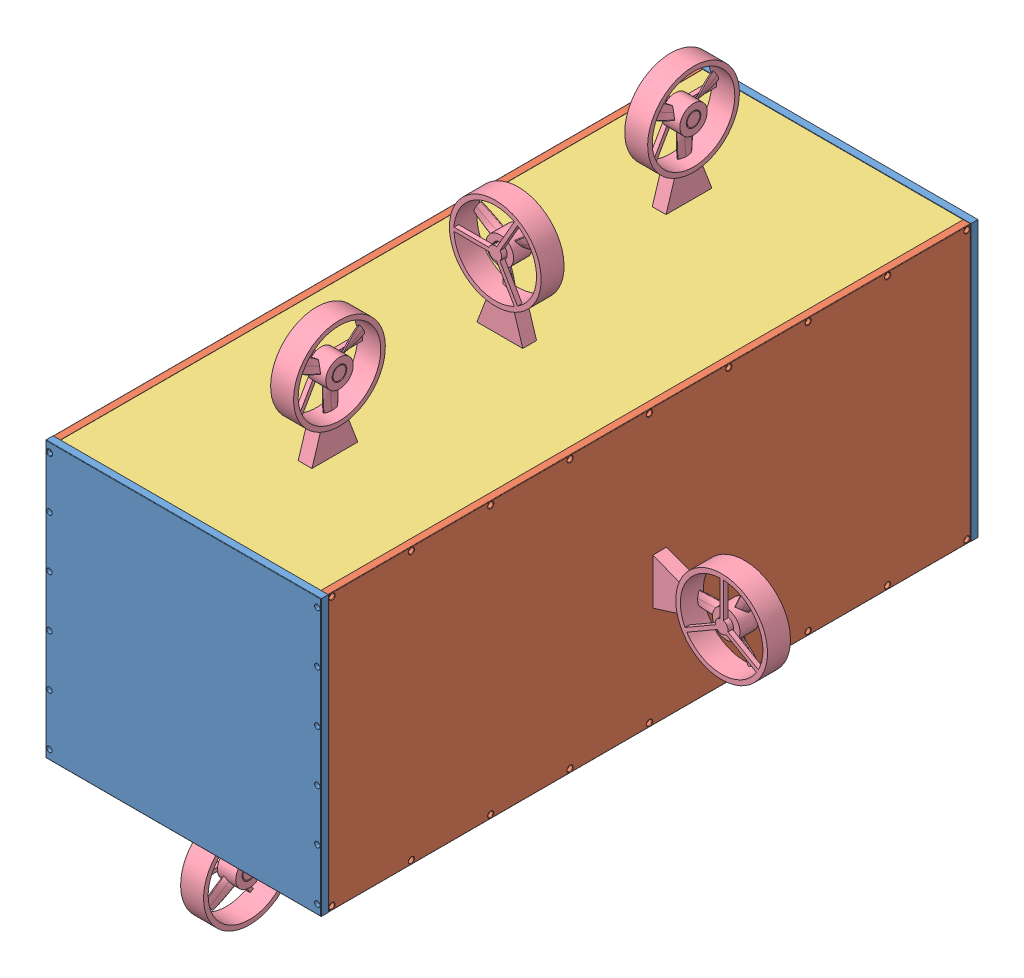
SolidWorks assembly square_assem, configuration Default. Lengths in mm.
Overall size (560 560 716).
14 component instances, 4 part files, 27 mates.
Components (placement in the parent):
- back_plate-1: back_plate [Default] at (111.4214 233.5106 160.385) size (300 300 8)
- side_plate-3: side_plate [Default] at (119.4214 233.5106 -539.615) x (0 0 1) z (-1 0 0) size (700 300 8)
- side_plate-4: side_plate [Default] at (403.4214 233.5106 160.385) x (0 0 -1) z (1 0 0) size (700 300 8)
- top_plate-3: top_plate [Default] at (119.4214 241.2606 160.385) x (0 0 -1) z (0 -1 0) size (700 284 8)
- top_plate-4: top_plate [Default] at (119.4214 533.2606 160.385) x (0 0 -1) z (0 -1 0) size (700 284 8)
- back_plate-2: back_plate [Default] at (111.4214 233.5106 -547.615) size (300 300 8)
- thruster-3: thruster [Default] at (491.4214 369.0106 -213.2381) size (130 100 25)
- thruster-4: thruster [Default] at (252.0667 153.2606 -221.0968) x (0 -1 0) z (0 0 1) size (130 100 25)
- thruster-5: thruster [Default] at (259.8092 613.2606 -198.1374) x (0 1 0) z (0 0 1) size (130 100 25)
- thruster-6: thruster [Default] at (31.4214 373.3341 -132.5652) x (-1 0 0) z (0 0 -1) size (130 100 25)
- thruster-9: thruster [Default] at (288.1941 613.2606 25.0544) x (0 1 0) z (-1 0 0) size (130 100 25)
- thruster-10: thruster [Default] at (241.5001 613.2606 -407.5213) x (0 1 0) z (-1 0 0) size (130 100 25)
- thruster-12: thruster [Default] at (249.9214 153.2606 84.885) x (0 -1 0) z (-1 0 0) size (130 100 25)
- thruster-13: thruster [Default] at (249.9214 153.2606 -487.0787) x (0 -1 0) z (-1 0 0) size (130 100 25)
Mates (geometry in assembly coordinates):
- Concentric3: concentric aligned: cylinder of back_plate-1 through (115.4214 243.5106 160.384) axis (0 0 1) radius 1.5; cylinder of side_plate-3 through (115.4214 243.5106 140.385) axis (0 0 1) radius 1.5
- Coincident5: coincident anti-aligned: plane of back_plate-1 through (111.4214 233.5106 160.385) normal (0 0 -1); plane of side_plate-3 through (111.4214 233.5106 160.385) normal (0 0 1)
- Concentric4: concentric aligned: cylinder of back_plate-1 through (115.4214 523.5106 160.384) axis (0 0 1) radius 1.5; cylinder of side_plate-3 through (115.4214 523.5106 140.385) axis (0 0 1) radius 1.5
- Concentric5: concentric aligned: cylinder of back_plate-1 through (407.4214 243.5106 160.384) axis (0 0 1) radius 1.5; cylinder of side_plate-4 through (407.4214 243.5106 140.385) axis (0 0 1) radius 1.5
- Concentric6: concentric aligned: cylinder of back_plate-1 through (407.4214 523.5106 160.384) axis (0 0 1) radius 1.5; cylinder of side_plate-4 through (407.4214 523.5106 140.385) axis (0 0 1) radius 1.5
- Coincident6: coincident anti-aligned: plane of back_plate-1 through (111.4214 233.5106 160.385) normal (0 0 -1); plane of side_plate-4 through (411.4214 233.5106 160.385) normal (0 0 1)
- Concentric7: concentric aligned: cylinder of side_plate-3 through (115.4214 237.5106 -449.115) axis (-1 0 0) radius 3; cylinder of top_plate-3 through (139.4214 237.5106 -449.115) axis (-1 0 0) radius 1.5
- Coincident7: coincident anti-aligned: plane of side_plate-4 through (403.4214 233.5106 160.385) normal (-1 0 0); plane of top_plate-3 through (403.4214 233.2606 160.385) normal (1 0 0)
- Concentric8: concentric aligned: cylinder of side_plate-3 through (115.4214 529.5106 69.885) axis (-1 0 0) radius 3; cylinder of top_plate-4 through (139.4214 529.5106 69.885) axis (-1 0 0) radius 1.5
- Coincident8: coincident anti-aligned: plane of side_plate-3 through (119.4214 233.5106 -539.615) normal (1 0 0); plane of top_plate-4 through (119.4214 525.2606 160.385) normal (-1 0 0)
- Concentric9: concentric anti-aligned: cylinder of side_plate-3 through (115.4214 523.5106 -519.615) axis (0 0 -1) radius 1.5; cylinder of back_plate-2 through (115.4214 523.5106 -547.616) axis (0 0 1) radius 1.5
- Coincident9: coincident anti-aligned: plane of side_plate-3 through (111.4214 233.5106 -539.615) normal (0 0 -1); plane of back_plate-2 through (111.4214 233.5106 -539.615) normal (0 0 1)
- Coincident10: coincident anti-aligned: plane of side_plate-4 through (411.4214 233.5106 160.385) normal (1 0 0); plane of thruster-3 through (411.4214 369.0106 -208.2381) normal (-1 0 0)
- Coincident11: coincident anti-aligned: plane of top_plate-3 through (119.4214 233.2606 160.385) normal (0 -1 0); plane of thruster-4 through (252.0667 233.2606 -216.0968) normal (0 1 0)
- Distance1: distance = 110 mm: line of thruster-3 through (411.4214 344.0106 -208.2381) axis (0 0 1); line of side_plate-4 through (411.4214 234.0106 -189.615) axis (0 0 -1)
- Coincident14: coincident anti-aligned: plane of top_plate-4 through (119.4214 533.2606 160.385) normal (0 1 0); plane of thruster-5 through (259.8092 533.2606 -193.1374) normal (0 -1 0)
- Coincident15: coincident anti-aligned: plane of side_plate-3 through (111.4214 233.5106 -539.615) normal (-1 0 0); plane of thruster-6 through (111.4214 373.3341 -137.5652) normal (1 0 0)
- Parallel1: parallel anti-aligned: line of side_plate-3 through (111.4214 237.5106 159.885) axis (0 1 0); line of thruster-6 through (111.4214 398.3341 -137.5652) axis (0 -1 0)
- Coincident18: coincident anti-aligned: plane of top_plate-4 through (119.4214 533.2606 160.385) normal (0 1 0); plane of thruster-9 through (283.1941 533.2606 25.0544) normal (0 -1 0)
- Coincident19: coincident anti-aligned: plane of top_plate-4 through (119.4214 533.2606 160.385) normal (0 1 0); plane of thruster-10 through (236.5001 533.2606 -407.5213) normal (0 -1 0)
- Parallel2: parallel anti-aligned: line of side_plate-3 through (119.4214 533.5106 160.385) axis (0 0 -1); line of thruster-10 through (221.5001 533.2606 -432.5213) axis (0 0 1)
- Parallel3: parallel anti-aligned: line of side_plate-3 through (119.4214 533.5106 160.385) axis (0 0 -1); line of thruster-9 through (268.1941 533.2606 0.0544) axis (0 0 1)
- Lock1: lock: unknown of side_plate-4; unknown of top_plate-3
- Parallel8: parallel aligned: line of top_plate-3 through (402.9214 233.2606 159.885) axis (-1 0 0); line of thruster-12 through (244.9214 233.2606 109.885) axis (-1 0 0)
- Coincident27: coincident anti-aligned: plane of top_plate-3 through (119.4214 233.2606 160.385) normal (0 -1 0); plane of thruster-12 through (244.9214 233.2606 84.885) normal (0 1 0)
- Distance5: distance = 110 mm: line of thruster-12 through (229.9214 233.2606 109.885) axis (0 0 -1); line of top_plate-3 through (119.9214 233.2606 159.885) axis (0 0 -1)
- Distance6: distance = 50 mm: line of thruster-12 through (244.9214 233.2606 109.885) axis (-1 0 0); line of top_plate-3 through (402.9214 233.2606 159.885) axis (-1 0 0)
